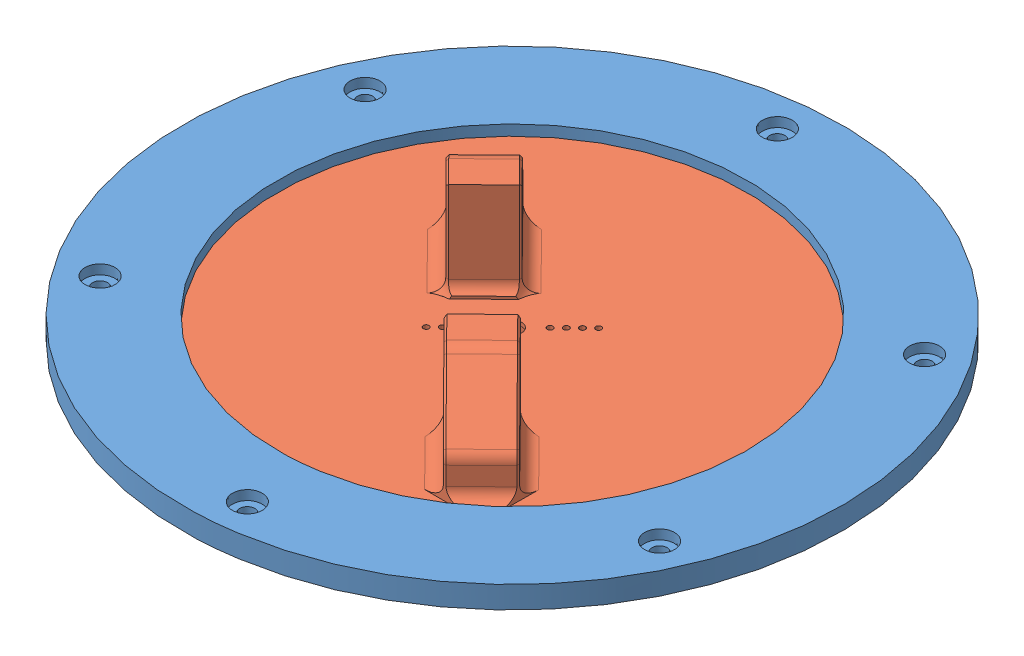
SolidWorks assembly baseLink_rotation_assembly, configuration Default. Lengths in mm.
Overall size (197.99 33 197.99).
4 component instances, 4 part files, 8 mates.
Components (placement in the parent):
- Part 3-1: Part 3 [Default] at (-136.6078 10.8 5.6277) x (0.995168 0 -0.098186) z (0.098186 0 0.995168) size (173 5.8 173)
- Part 1-1: Part 1 [Default] at (-136.6078 0 5.6277) x (0.995168 0 -0.098186) z (0.098186 0 0.995168) size (173 5.8 173) (hidden)
- twisting_link_base-1: twisting_link_base [Default] at (-235.1026 -42.3165 -38.6597) x (0.711905 0 -0.702276) z (0.702276 0 0.711905) size (140 33 140)
- MG995_Gear2-1: MG995_Gear2 [Défaut] at (-136.6078 10.8 5.6277) x (-0.697661 0 -0.716429) z (0 -1 0) size (11.5 38 5)
Mates (geometry in assembly coordinates):
- Coincident3: coincident anti-aligned: plane of Part 1-1 through (-136.6078 5.8 5.6277) normal (0 1 0); plane of twisting_link_base-1 through (-136.6078 5.8 5.6277) normal (0 -1 0)
- Concentric10: concentric aligned: circle of Part 3-1; circle of Part 1-1
- Concentric8: concentric anti-aligned: circle of Part 3-1; circle of Part 1-1
- Coincident9: coincident anti-aligned: plane of Part 3-1 through (-136.6078 13.8 5.6277) normal (0 -1 0); plane of twisting_link_base-1 through (-136.6078 13.8 5.6277) normal (0 1 0)
- Coincident11: coincident anti-aligned: plane of Part 1-1 through (-136.6078 0 5.6277) normal (0 -1 0)
- Concentric11: concentric anti-aligned: circle of Part 1-1; circle of twisting_link_base-1
- Concentric14: concentric anti-aligned: circle of twisting_link_base-1; circle of MG995_Gear2-1
- Coincident15: coincident anti-aligned: plane of twisting_link_base-1 through (-136.6078 10.8 5.6277) normal (0 -1 0); plane of MG995_Gear2-1 through (-136.6078 10.8 5.6277) normal (0 1 0)
